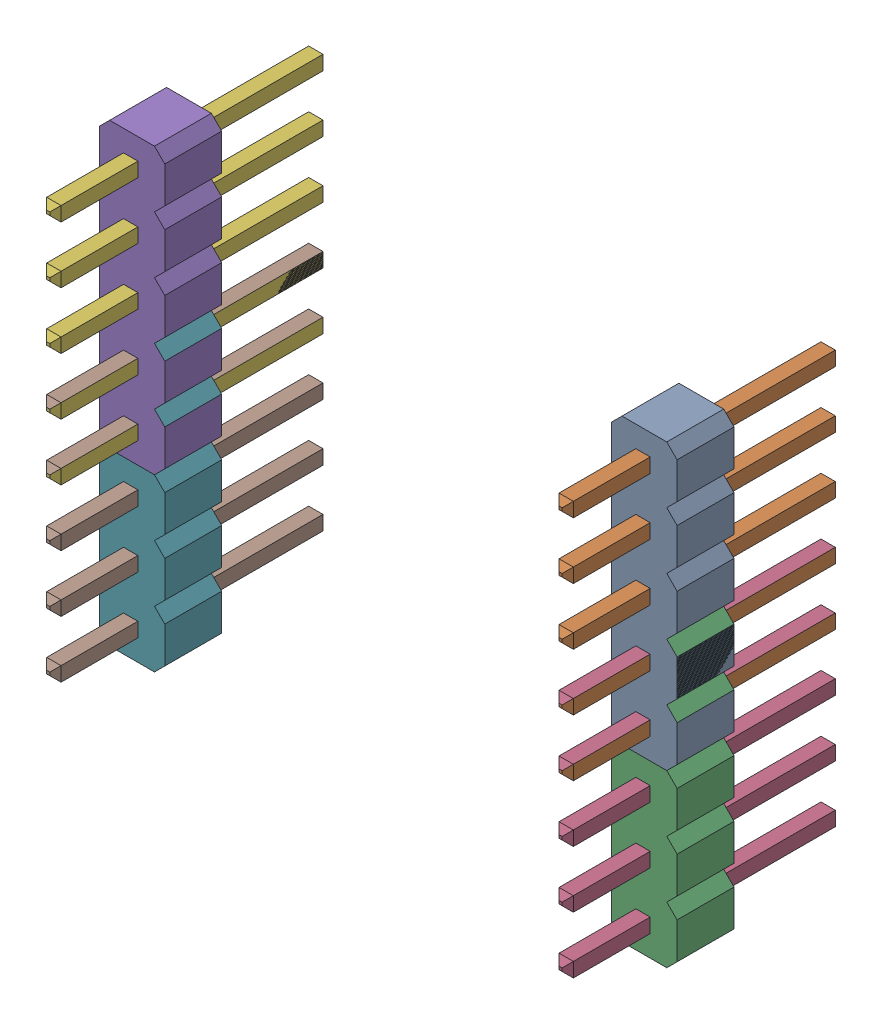
SolidWorks assembly MBD1.step, configuration Default. Lengths in mm.
Overall size (25.78 20.32 12.19).
18 component instances, 2 part files, 0 mates.
Components (placement in the parent):
- Header_1x8.step-1: Header_1x8.step [Default] at (-74.8548 -67.056 0) size (2.92 20.32 12.19)
  - PCB.step-1: PCB.step [Default] at origin size (2.92 20.32 12.19)
    - Free-Models.step-1: Free-Models.step [Default] at origin size (2.92 20.32 12.19)
      - 1240637040.step-1: 1240637040.step [Default] at (97.7778 84.836 -1.6002) x (0 -1 0) z (1 0 0) size (12.7 12.19 2.92)
        - User_Library-PinHeaderX5-1_PinHeaderX5_Body_1.step-1: User_Library-PinHeaderX5-1_PinHeaderX5_Body_1.step [Default] at origin size (12.7 2.54 2.92)
        - User_Library-PinHeaderX5-1_PinHeaderX5_Pins_1.step-1: User_Library-PinHeaderX5-1_PinHeaderX5_Pins_1.step [Default] at origin size (10.8 12.19 0.64)
      - 1240637040.step-2: 1240637040.step [Default] at (97.7778 77.216 -1.6002) x (0 -1 0) z (1 0 0) size (12.7 12.19 2.92)
        - User_Library-PinHeaderX5-1_PinHeaderX5_Body_1.step-1: User_Library-PinHeaderX5-1_PinHeaderX5_Body_1.step [Default] at origin size (12.7 2.54 2.92)
        - User_Library-PinHeaderX5-1_PinHeaderX5_Pins_1.step-1: User_Library-PinHeaderX5-1_PinHeaderX5_Pins_1.step [Default] at origin size (10.8 12.19 0.64)
- Header_1x8.step-2: Header_1x8.step [Default] at (-97.7148 -67.056 0) size (2.92 20.32 12.19)
  - PCB.step-1: PCB.step [Default] at origin size (2.92 20.32 12.19)
    - Free-Models.step-1: Free-Models.step [Default] at origin size (2.92 20.32 12.19)
      - 1240637040.step-1: 1240637040.step [Default] at (97.7778 84.836 -1.6002) x (0 -1 0) z (1 0 0) size (12.7 12.19 2.92)
        - User_Library-PinHeaderX5-1_PinHeaderX5_Body_1.step-1: User_Library-PinHeaderX5-1_PinHeaderX5_Body_1.step [Default] at origin size (12.7 2.54 2.92)
        - User_Library-PinHeaderX5-1_PinHeaderX5_Pins_1.step-1: User_Library-PinHeaderX5-1_PinHeaderX5_Pins_1.step [Default] at origin size (10.8 12.19 0.64)
      - 1240637040.step-2: 1240637040.step [Default] at (97.7778 77.216 -1.6002) x (0 -1 0) z (1 0 0) size (12.7 12.19 2.92)
        - User_Library-PinHeaderX5-1_PinHeaderX5_Body_1.step-1: User_Library-PinHeaderX5-1_PinHeaderX5_Body_1.step [Default] at origin size (12.7 2.54 2.92)
        - User_Library-PinHeaderX5-1_PinHeaderX5_Pins_1.step-1: User_Library-PinHeaderX5-1_PinHeaderX5_Pins_1.step [Default] at origin size (10.8 12.19 0.64)
